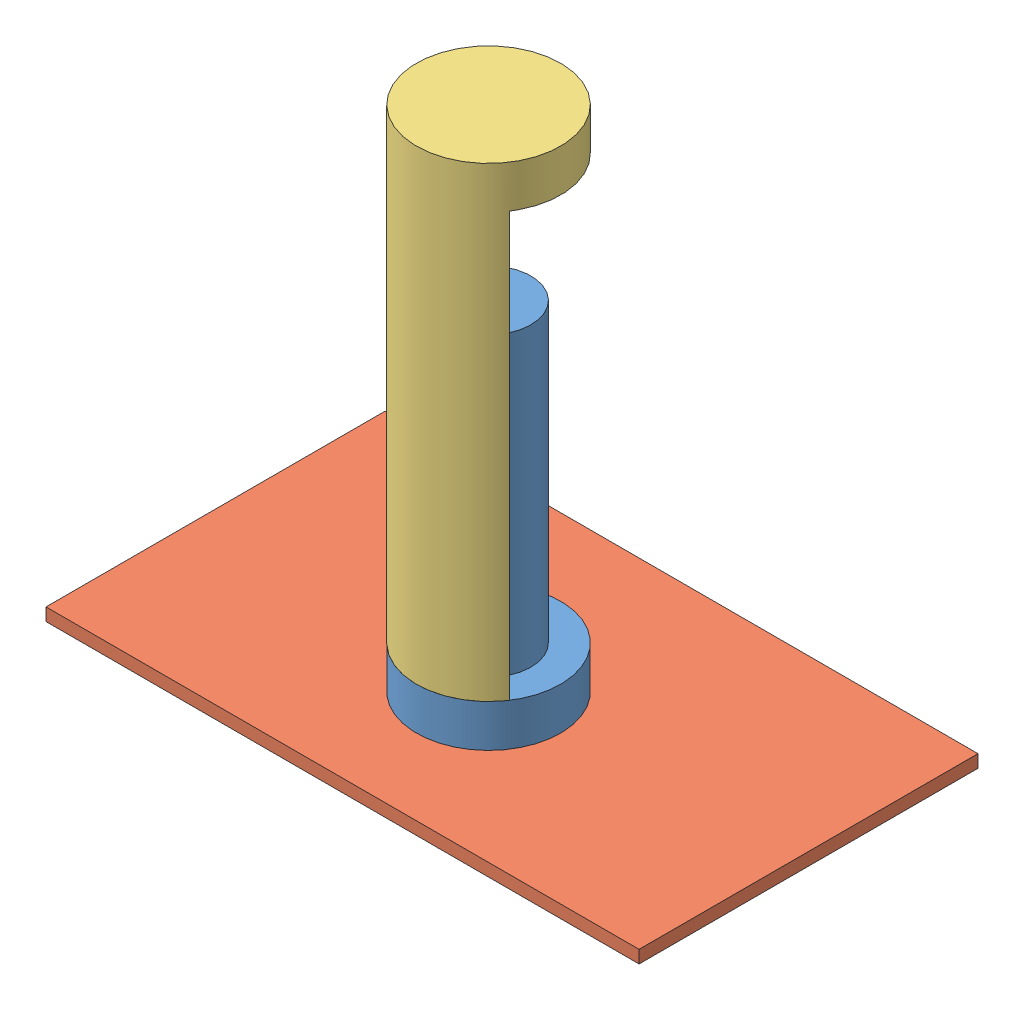
SolidWorks assembly Assemblage1, configuration Défaut. Lengths in mm.
Overall size (140 123 80).
3 component instances, 3 part files, 2 mates.
Components (placement in the parent):
- pieceInterieure-1: pieceInterieure [Défaut] at (105.977 -1.4135 158.7108) x (-0.852259 0 -0.52312) z (-0.52312 0 0.852259) size (34 80 34)
- sol-1: sol [Défaut] at (96.4177 -84.4135 153.6143) size (140 3 80)
- pieceExterieure-2: pieceExterieure [Défaut] at (105.977 28.5865 158.7108) x (0.837169 0 0.546944) z (0.546944 0 -0.837169) size (34 110 34)
Mates (geometry in assembly coordinates):
- Parallèle1: parallel anti-aligned: plane of pieceInterieure-1 through (105.977 -81.4135 158.7108) normal (0 -1 0); plane of sol-1 through (96.4177 -81.4135 153.6143) normal (0 1 0)
- Coaxiale4: concentric: cylinder of pieceInterieure-1 through (105.977 -71.4135 158.7108) axis (0 1 0) radius 10; cylinder of pieceExterieure-2 through (105.977 -71.4135 158.7108) axis (0 1 0) radius 10.5
